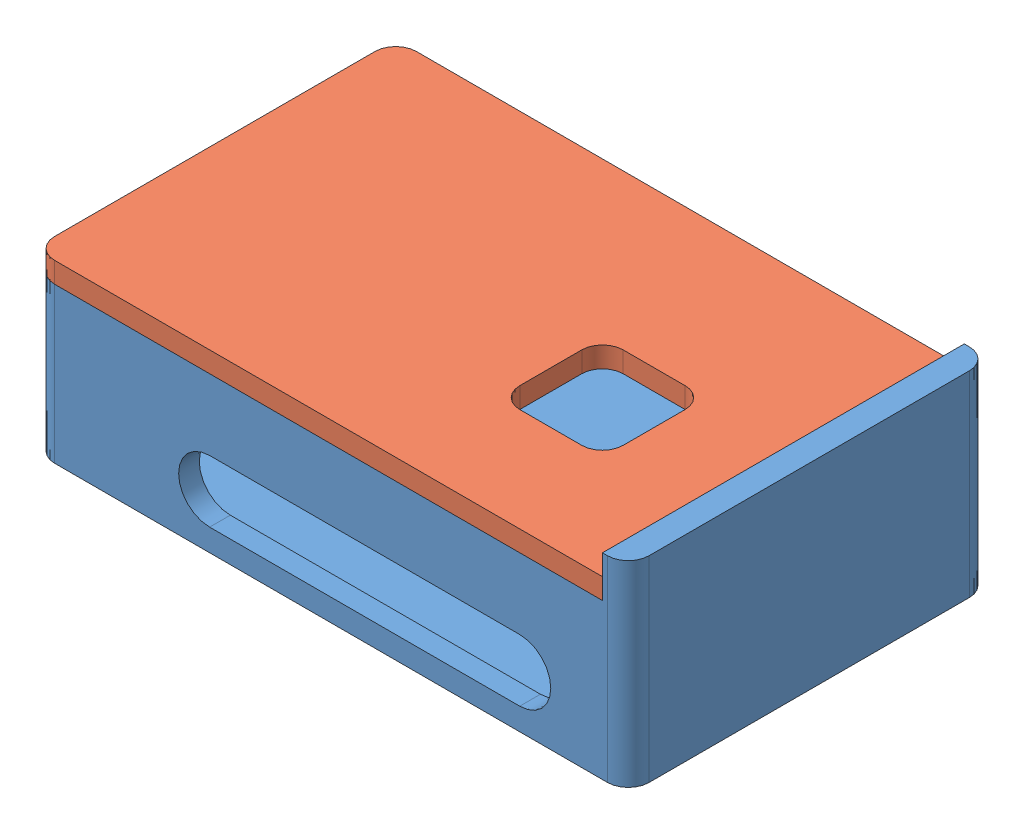
SolidWorks assembly Assem1, configuration Default. Lengths in mm.
Overall size (146.05 48.26 88.9).
2 component instances, 2 part files, 3 mates.
Components (placement in the parent):
- Back Casing-1: Back Casing [Default] at (42.8602 53.9351 130.6631) size (146.05 48.26 88.9)
- Front Plate-2: Front Plate [Default] at (26.4633 92.0351 128.1481) x (0 1 0) z (-1 0 0) size (17.78 88.9 139.7)
Mates (geometry in assembly coordinates):
- Concentric1: concentric aligned: cylinder of Back Casing-1 through (88.8076 59.0151 160.7478) axis (0 1 0) radius 2.54; cylinder of Front Plate-2 through (88.8076 79.3351 160.7478) axis (0 1 0) radius 1.905
- Concentric2: concentric aligned: cylinder of Back Casing-1 through (-35.6524 59.0151 160.7478) axis (0 1 0) radius 2.54; cylinder of Front Plate-2 through (-35.6524 79.3351 160.7478) axis (0 1 0) radius 1.905
- Coincident1: coincident aligned: line of Back Casing-1 through (-38.1924 92.0351 168.3678) axis (1 0 0); line of Front Plate-2 through (-38.1924 92.0351 168.3678) axis (1 0 0)
